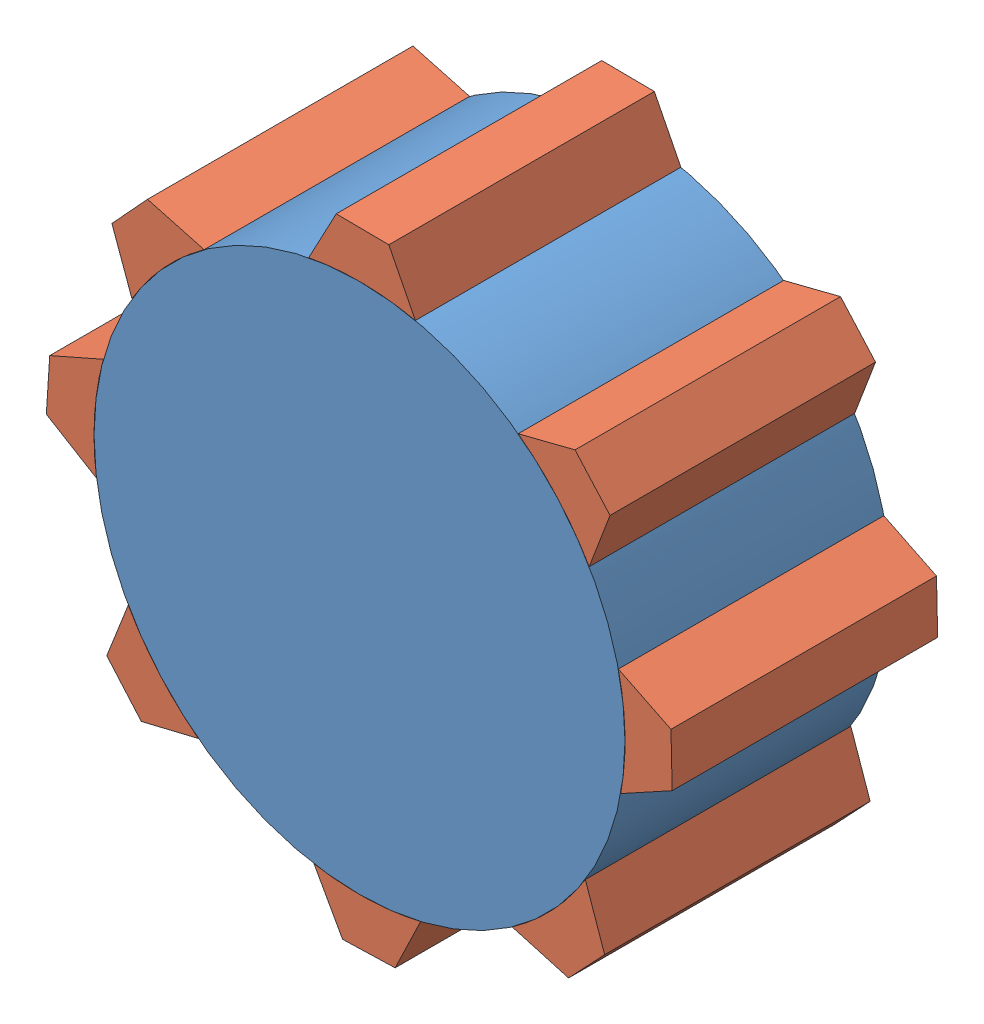
SolidWorks assembly Assem4, configuration Default. Lengths in mm.
Overall size (23.66 23.59 10).
9 component instances, 2 part files, 17 mates.
Components (placement in the parent):
- Part2-2: Part2 [Default] at origin size (20 20 10)
- Part3-1: Part3 [Default] x (0.999953 -0.009697 0) z (0 0 1) size (4.02 1.96 10)
- Part3-2: Part3 [Default] x (0.665397 -0.746489 0) z (0 0 1) size (4.02 1.96 10)
- Part3-3: Part3 [Default] x (0.022558 -0.999746 0) z (0 0 1) size (4.02 1.96 10)
- Part3-4: Part3 [Default] x (-0.686073 -0.727533 0) z (0 0 1) size (4.02 1.96 10)
- Part3-5: Part3 [Default] x (-0.999552 -0.029925 0) z (0 0 1) size (4.02 1.96 10)
- Part3-6: Part3 [Default] x (-0.656403 0.75441 0) z (0 0 1) size (4.02 1.96 10)
- Part3-7: Part3 [Default] x (0.06439 0.997925 0) z (0 0 1) size (4.02 1.96 10)
- Part3-8: Part3 [Default] x (0.676681 0.736277 0) z (0 0 1) size (4.02 1.96 10)
Mates (geometry in assembly coordinates):
- Coincident1: coordinate: point of Part2-2
- Concentric1: concentric aligned: cylinder of Part2-2 through (0 0 10) axis (0 0 -1) radius 10; cylinder of Part3-5 through (0 0 10) axis (0 0 -1) radius 10
- Concentric2: concentric aligned: cylinder of Part2-2 through (0 0 10) axis (0 0 -1) radius 10; cylinder of Part3-8 through (0 0 10) axis (0 0 -1) radius 10
- Concentric3: concentric aligned: cylinder of Part2-2 through (0 0 10) axis (0 0 -1) radius 10; cylinder of Part3-4 through (0 0 10) axis (0 0 -1) radius 10
- Concentric4: concentric aligned: cylinder of Part2-2 through (0 0 10) axis (0 0 -1) radius 10; cylinder of Part3-2 through (0 0 10) axis (0 0 -1) radius 10
- Concentric5: concentric aligned: cylinder of Part2-2 through (0 0 10) axis (0 0 -1) radius 10; cylinder of Part3-3 through (0 0 10) axis (0 0 -1) radius 10
- Concentric6: concentric aligned: cylinder of Part2-2 through (0 0 10) axis (0 0 -1) radius 10; cylinder of Part3-7 through (0 0 10) axis (0 0 -1) radius 10
- Concentric7: concentric aligned: cylinder of Part2-2 through (0 0 10) axis (0 0 -1) radius 10; cylinder of Part3-1 through (0 0 10) axis (0 0 -1) radius 10
- Concentric8: concentric aligned: cylinder of Part2-2 through (0 0 10) axis (0 0 -1) radius 10; cylinder of Part3-6 through (0 0 10) axis (0 0 -1) radius 10
- Coincident3: coincident aligned: plane of Part2-2 through (0 0 10) normal (0 0 1); plane of Part3-8 through (0 0 10) normal (0 0 1)
- Coincident4: coincident aligned: plane of Part2-2 through (0 0 10) normal (0 0 1); plane of Part3-1 through (0 0 10) normal (0 0 1)
- Coincident5: coincident aligned: plane of Part2-2 through (0 0 10) normal (0 0 1); plane of Part3-2 through (0 0 10) normal (0 0 1)
- Coincident6: coincident aligned: plane of Part2-2 through (0 0 10) normal (0 0 1); plane of Part3-3 through (0 0 10) normal (0 0 1)
- Coincident7: coincident aligned: plane of Part2-2 through (0 0 10) normal (0 0 1); plane of Part3-4 through (0 0 10) normal (0 0 1)
- Coincident8: coincident aligned: plane of Part2-2 through (0 0 10) normal (0 0 1); plane of Part3-5 through (0 0 10) normal (0 0 1)
- Coincident9: coincident aligned: plane of Part2-2 through (0 0 10) normal (0 0 1); plane of Part3-7 through (0 0 10) normal (0 0 1)
- Coincident10: coincident aligned: plane of Part2-2 through (0 0 10) normal (0 0 1); plane of Part3-6 through (0 0 10) normal (0 0 1)
